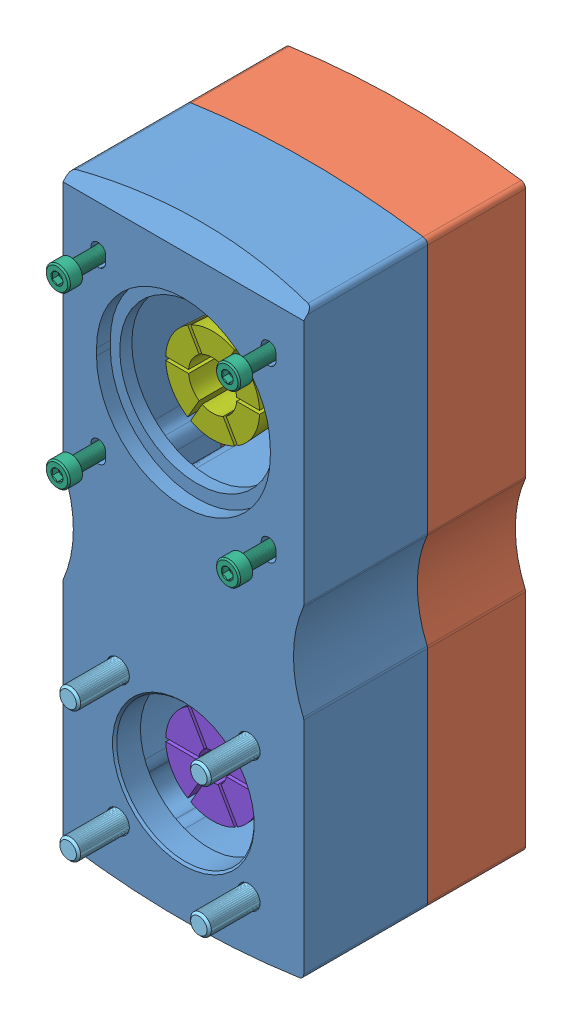
SolidWorks assembly 2617488 EAMM-U-70-D40-60P-96, configuration Default. Lengths in mm.
Overall size (70 173.5 79).
21 component instances, 8 part files, 30 mates.
Components (placement in the parent):
- 2607475 EAMM-U-70-D40-60P-96---(UT)-1: 2607475 EAMM-U-70-D40-60P-96---(UT) [Default] at (0 139 0) x (1 0 0) z (0 1 0) size (70 36 173.5)
- 2610112 EAMM-U-70-D40-___-173---(OT)-1: 2610112 EAMM-U-70-D40-___-173---(OT) [Default] at (0 139 -36) x (1 0 0) z (0 1 0) size (70 28.5 173.5)
- DIN-912 - M5x35(F)-1: DIN-912 - M5x35(F) [Default] at (29 -10 -58.5) x (1 0 0) z (0 1 0) size (8.5 40.23 8.5)
- DIN-912 - M5x35(F)-2: DIN-912 - M5x35(F) [Default] at (29 32.5 -58.5) x (1 0 0) z (0 1 0) size (8.5 40.23 8.5)
- DIN-912 - M5x35(F)-3: DIN-912 - M5x35(F) [Default] at (-29 -10 -58.5) x (1 0 0) z (0 1 0) size (8.5 40.23 8.5)
- DIN-912 - M5x35(F)-4: DIN-912 - M5x35(F) [Default] at (-29 32.5 -58.5) x (1 0 0) z (0 1 0) size (8.5 40.23 8.5)
- DIN-912 - M5x35(F)-5: DIN-912 - M5x35(F) [Default] at (0 133 -58.5) x (1 0 0) z (0 1 0) size (8.5 40.23 8.5)
- DIN 557 - M4-1: DIN 557 - M4 [Default] at (24.7487 120.7487 -3.4) x (0 0 -1) z (-0.707107 -0.707107 0) size (3.2 8.9 8.9)
- DIN 557 - M4-2: DIN 557 - M4 [Default] at (24.7487 71.2513 -3.4) x (0 0 -1) z (-0.707107 -0.707107 0) size (3.2 8.9 8.9)
- DIN 557 - M4-3: DIN 557 - M4 [Default] at (-24.7487 71.2513 -3.4) x (0 0 -1) z (-0.707107 -0.707107 0) size (3.2 8.9 8.9)
- DIN 557 - M4-4: DIN 557 - M4 [Default] at (-24.7487 120.7487 -3.4) x (0 0 -1) z (-0.707107 -0.707107 0) size (3.2 8.9 8.9)
- DIN-6912 - M6x18(F)-1: DIN-6912 - M6x18(F) [Default] at (19 19 -3.5) x (0 0 1) z (-1 0 0) size (22.29 10 10)
- DIN-6912 - M6x18(F)-2: DIN-6912 - M6x18(F) [Default] at (19 -19 -3.5) x (0 0 1) z (-1 0 0) size (22.29 10 10)
- DIN-6912 - M6x18(F)-3: DIN-6912 - M6x18(F) [Default] at (-19 19 -3.5) x (0 0 1) z (-1 0 0) size (22.29 10 10)
- DIN-6912 - M6x18(F)-4: DIN-6912 - M6x18(F) [Default] at (-19 -19 -3.5) x (0 0 1) z (-1 0 0) size (22.29 10 10)
- DIN-912 - M4x16(F)-1: DIN-912 - M4x16(F) [Default] at (24.7487 120.7487 8) x (1 0 0) z (0 -1 0) size (7 20.17 7)
- DIN-912 - M4x16(F)-2: DIN-912 - M4x16(F) [Default] at (24.7487 71.2513 8) x (1 0 0) z (0 -1 0) size (7 20.17 7)
- DIN-912 - M4x16(F)-3: DIN-912 - M4x16(F) [Default] at (-24.7487 71.2513 8) x (1 0 0) z (0 -1 0) size (7 20.17 7)
- DIN-912 - M4x16(F)-4: DIN-912 - M4x16(F) [Default] at (-24.7487 120.7487 8) x (1 0 0) z (0 -1 0) size (7 20.17 7)
- 2429534 EAMH-86-14-C27_3-1: 2429534 EAMH-86-14-C27_3 [Default] at (0 96 -48.5) x (0 0 1) z (-1 0 0) size (40.22 27.3 27.28)
- 2429531 EAMH-86-8-C27_3-1: 2429531 EAMH-86-8-C27_3 [Default] at (0 0 -48.5) x (0 0 1) z (-1 0 0) size (40.22 27.3 27.28)
Mates (geometry in assembly coordinates):
- Distance1: distance = 0 mm anti-aligned: plane of 2607475 EAMM-U-70-D40-60P-96---(UT)-1 through (0 139 -3.5) normal (0 0 -1); plane of DIN-6912 - M6x18(F)-1 through (19 19 -3.5) normal (0 0 1)
- Coincident1: coincident anti-aligned: line of 2607475 EAMM-U-70-D40-60P-96---(UT)-1 through (19 19 -50) axis (0 0 1); line of DIN-6912 - M6x18(F)-1 through (19 19 77.4) axis (0 0 -1)
- Angle3: planar angle = 0 rad aligned: plane of DIN-6912 - M6x18(F)-1 through (19 19 -3.5) normal (1 0 0); plane of 2607475 EAMM-U-70-D40-60P-96---(UT)-1 through (19 139 0) normal (1 0 0)
- Distance2: distance = 0 mm anti-aligned: plane of 2607475 EAMM-U-70-D40-60P-96---(UT)-1 through (0 139 -3.5) normal (0 0 -1); plane of DIN-6912 - M6x18(F)-2 through (19 -19 -3.5) normal (0 0 1)
- Coincident2: coincident anti-aligned: line of 2607475 EAMM-U-70-D40-60P-96---(UT)-1 through (19 -19 -50) axis (0 0 1); line of DIN-6912 - M6x18(F)-2 through (19 -19 77.4) axis (0 0 -1)
- Angle6: planar angle = 0 rad aligned: plane of DIN-6912 - M6x18(F)-2 through (19 -19 -3.5) normal (1 0 0); plane of 2607475 EAMM-U-70-D40-60P-96---(UT)-1 through (19 139 0) normal (1 0 0)
- Distance3: distance = 0 mm anti-aligned: plane of 2607475 EAMM-U-70-D40-60P-96---(UT)-1 through (0 139 -3.5) normal (0 0 -1); plane of DIN-6912 - M6x18(F)-3 through (-19 19 -3.5) normal (0 0 1)
- Coincident3: coincident anti-aligned: line of 2607475 EAMM-U-70-D40-60P-96---(UT)-1 through (-19 19 -50) axis (0 0 1); line of DIN-6912 - M6x18(F)-3 through (-19 19 77.4) axis (0 0 -1)
- Angle9: planar angle = 0 rad aligned: plane of DIN-6912 - M6x18(F)-3 through (-19 19 -3.5) normal (1 0 0); plane of 2607475 EAMM-U-70-D40-60P-96---(UT)-1 through (-19 139 0) normal (1 0 0)
- Distance4: distance = 0 mm anti-aligned: plane of 2607475 EAMM-U-70-D40-60P-96---(UT)-1 through (0 139 -3.5) normal (0 0 -1); plane of DIN-6912 - M6x18(F)-4 through (-19 -19 -3.5) normal (0 0 1)
- Coincident4: coincident anti-aligned: line of 2607475 EAMM-U-70-D40-60P-96---(UT)-1 through (-19 -19 -50) axis (0 0 1); line of DIN-6912 - M6x18(F)-4 through (-19 -19 77.4) axis (0 0 -1)
- Angle12: planar angle = 0 rad aligned: plane of DIN-6912 - M6x18(F)-4 through (-19 -19 -3.5) normal (1 0 0); plane of 2607475 EAMM-U-70-D40-60P-96---(UT)-1 through (-19 139 0) normal (1 0 0)
- Distance5: distance = 0 mm anti-aligned: plane of 2607475 EAMM-U-70-D40-60P-96---(UT)-1 through (0 139 8) normal (0 0 -1); plane of DIN-912 - M4x16(F)-1 through (24.7487 120.7487 8) normal (0 0 1)
- Coincident5: coincident anti-aligned: line of 2607475 EAMM-U-70-D40-60P-96---(UT)-1 through (24.7487 120.7487 -50) axis (0 0 1); line of DIN-912 - M4x16(F)-1 through (24.7487 120.7487 58) axis (0 0 -1)
- Angle15: planar angle = 0 rad aligned: plane of DIN-912 - M4x16(F)-1 through (24.7487 120.7487 8) normal (1 0 0); plane of 2607475 EAMM-U-70-D40-60P-96---(UT)-1 through (24.7487 139 0) normal (1 0 0)
- Distance6: distance = 0 mm anti-aligned: plane of 2607475 EAMM-U-70-D40-60P-96---(UT)-1 through (0 139 8) normal (0 0 -1); plane of DIN-912 - M4x16(F)-2 through (24.7487 71.2513 8) normal (0 0 1)
- Coincident6: coincident anti-aligned: line of 2607475 EAMM-U-70-D40-60P-96---(UT)-1 through (24.7487 71.2513 -50) axis (0 0 1); line of DIN-912 - M4x16(F)-2 through (24.7487 71.2513 58) axis (0 0 -1)
- Angle18: planar angle = 0 rad aligned: plane of DIN-912 - M4x16(F)-2 through (24.7487 71.2513 8) normal (1 0 0); plane of 2607475 EAMM-U-70-D40-60P-96---(UT)-1 through (24.7487 139 0) normal (1 0 0)
- Distance7: distance = 0 mm anti-aligned: plane of 2607475 EAMM-U-70-D40-60P-96---(UT)-1 through (0 139 8) normal (0 0 -1); plane of DIN-912 - M4x16(F)-3 through (-24.7487 71.2513 8) normal (0 0 1)
- Coincident7: coincident anti-aligned: line of 2607475 EAMM-U-70-D40-60P-96---(UT)-1 through (-24.7487 71.2513 -50) axis (0 0 1); line of DIN-912 - M4x16(F)-3 through (-24.7487 71.2513 58) axis (0 0 -1)
- Angle21: planar angle = 0 rad aligned: plane of DIN-912 - M4x16(F)-3 through (-24.7487 71.2513 8) normal (1 0 0); plane of 2607475 EAMM-U-70-D40-60P-96---(UT)-1 through (-24.7487 139 0) normal (1 0 0)
- Distance8: distance = 0 mm anti-aligned: plane of 2607475 EAMM-U-70-D40-60P-96---(UT)-1 through (0 139 8) normal (0 0 -1); plane of DIN-912 - M4x16(F)-4 through (-24.7487 120.7487 8) normal (0 0 1)
- Coincident8: coincident anti-aligned: line of 2607475 EAMM-U-70-D40-60P-96---(UT)-1 through (-24.7487 120.7487 -50) axis (0 0 1); line of DIN-912 - M4x16(F)-4 through (-24.7487 120.7487 58) axis (0 0 -1)
- Angle24: planar angle = 0 rad aligned: plane of DIN-912 - M4x16(F)-4 through (-24.7487 120.7487 8) normal (1 0 0); plane of 2607475 EAMM-U-70-D40-60P-96---(UT)-1 through (-24.7487 139 0) normal (1 0 0)
- Distance9: distance = 0 mm anti-aligned: plane of 2607475 EAMM-U-70-D40-60P-96---(UT)-1 through (0 139 -8.5) normal (0 0 -1); plane of 2429534 EAMH-86-14-C27_3-1 through (0 96 -8.5) normal (0 0 1)
- Coincident9: coincident anti-aligned: line of 2607475 EAMM-U-70-D40-60P-96---(UT)-1 through (0 96 -50) axis (0 0 1); line of 2429534 EAMH-86-14-C27_3-1 through (0 96 32.4) axis (0 0 -1)
- Angle27: planar angle = 0 rad aligned: plane of 2429534 EAMH-86-14-C27_3-1 through (0 96 -48.5) normal (1 0 0); plane of 2607475 EAMM-U-70-D40-60P-96---(UT)-1 through (0 139 0) normal (1 0 0)
- Distance10: distance = 0 mm anti-aligned: plane of 2607475 EAMM-U-70-D40-60P-96---(UT)-1 through (0 139 -8.5) normal (0 0 -1); plane of 2429531 EAMH-86-8-C27_3-1 through (0 0 -8.5) normal (0 0 1)
- Coincident10: coincident anti-aligned: line of 2607475 EAMM-U-70-D40-60P-96---(UT)-1 through (0 0 -50) axis (0 0 1); line of 2429531 EAMH-86-8-C27_3-1 through (0 0 32.4) axis (0 0 -1)
- Angle30: planar angle = 0 rad aligned: plane of 2429531 EAMH-86-8-C27_3-1 through (0 0 -48.5) normal (1 0 0); plane of 2607475 EAMM-U-70-D40-60P-96---(UT)-1 through (0 139 0) normal (1 0 0)
